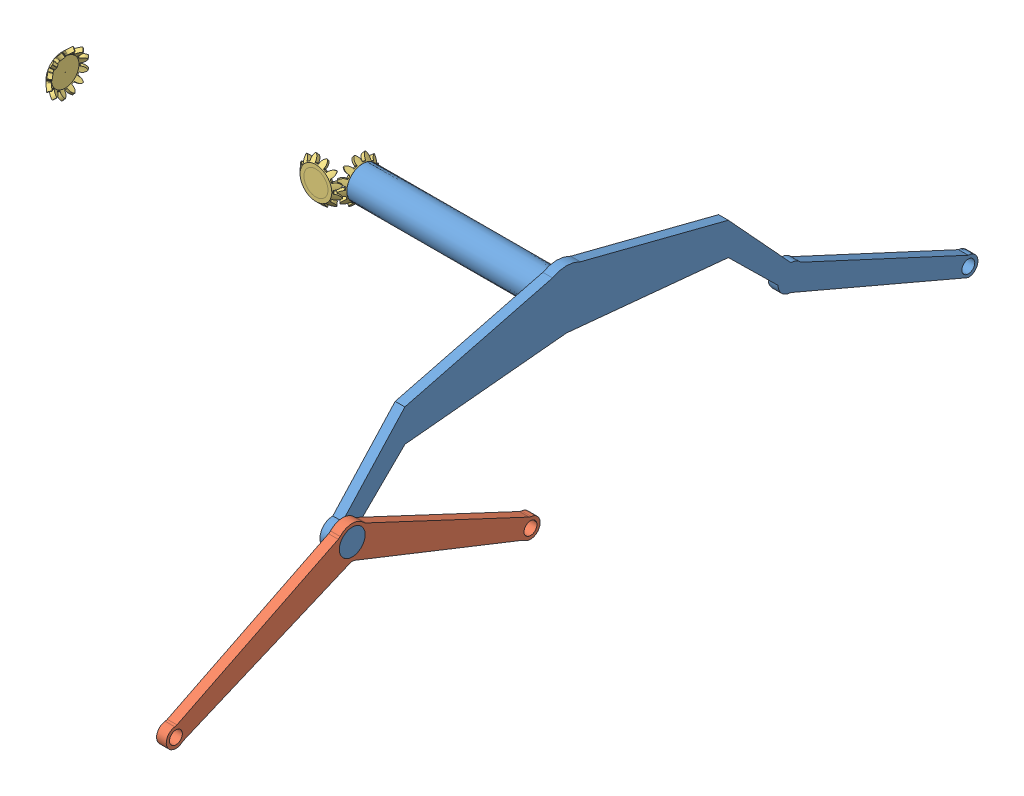
SolidWorks assembly Assem1, configuration Default. Lengths in mm.
Overall size (1608.88 658.52 2543.04).
5 component instances, 3 part files, 4 mates.
Components (placement in the parent):
- Rocker_0.1-1: Rocker_0.1 [Default] at (1324.7241 916.8798 677.0712) x (0.999999 0.001566 0) z (0 0 1) size (660 652.2 2004.4)
- Bogie_0.1-1: Bogie_0.1 [Default] at (1355.1753 628.7636 1370.2089) x (0.999999 0.001566 0) z (0.000017 -0.010876 0.999941) size (30 324.04 1156.25)
- straight bevel gear_am-1: straight bevel gear_am [Metric - Straight bevel gear 10M 12GT 12PT 20PA 12FW ---12O75H50MD0.8N] at (655.9658 916.926 753.3034) x (0.008727 0 -0.999962) z (0.999962 0 0.008727) size (25.19 132.73 132.73)
- straight bevel gear_am-2: straight bevel gear_am [Metric - Straight bevel gear 10M 12GT 12PT 20PA 12FW ---12O75H50MD0.8N] at (-223.2677 731.8802 659.0722) size (25.19 132.73 132.73)
- straight bevel gear_am-3: straight bevel gear_am [Metric - Straight bevel gear 10M 12GT 12PT 20PA 12FW ---12O75H50MD0.8N] at (724.7248 915.9404 677.0712) x (-0.999999 -0.001566 0) z (0.001447 -0.924224 -0.381849) size (25.19 132.73 132.73)
Mates (geometry in assembly coordinates):
- Hinge1: hinge: circle of Bogie_0.1-1; circle of Rocker_0.1-1; plane of Bogie_0.1-1 through (1355.1753 628.7636 1370.2089) normal (-0.999999 -0.001566 0); plane of Rocker_0.1-1 through (1354.7241 916.9268 677.0712) normal (0.999999 0.001566 0)
- Coincident1: coincident: plane of Rocker_0.1-1 through (724.7249 915.9404 677.0712) normal (-0.999999 -0.001566 0); plane of straight bevel gear_am-3 through (724.7249 915.9404 677.0712) normal (0.999999 0.001566 0)
- Concentric1: concentric: circle of Rocker_0.1-1; circle of straight bevel gear_am-3
- GearMate2: gear = 1 : 1 mm: cone of straight bevel gear_am-1 through (656.0528 916.926 743.3334) axis (-0.008727 0 0.999962); cone of straight bevel gear_am-3 through (714.7544 915.9248 677.0712) axis (0.999999 0.001566 0)
